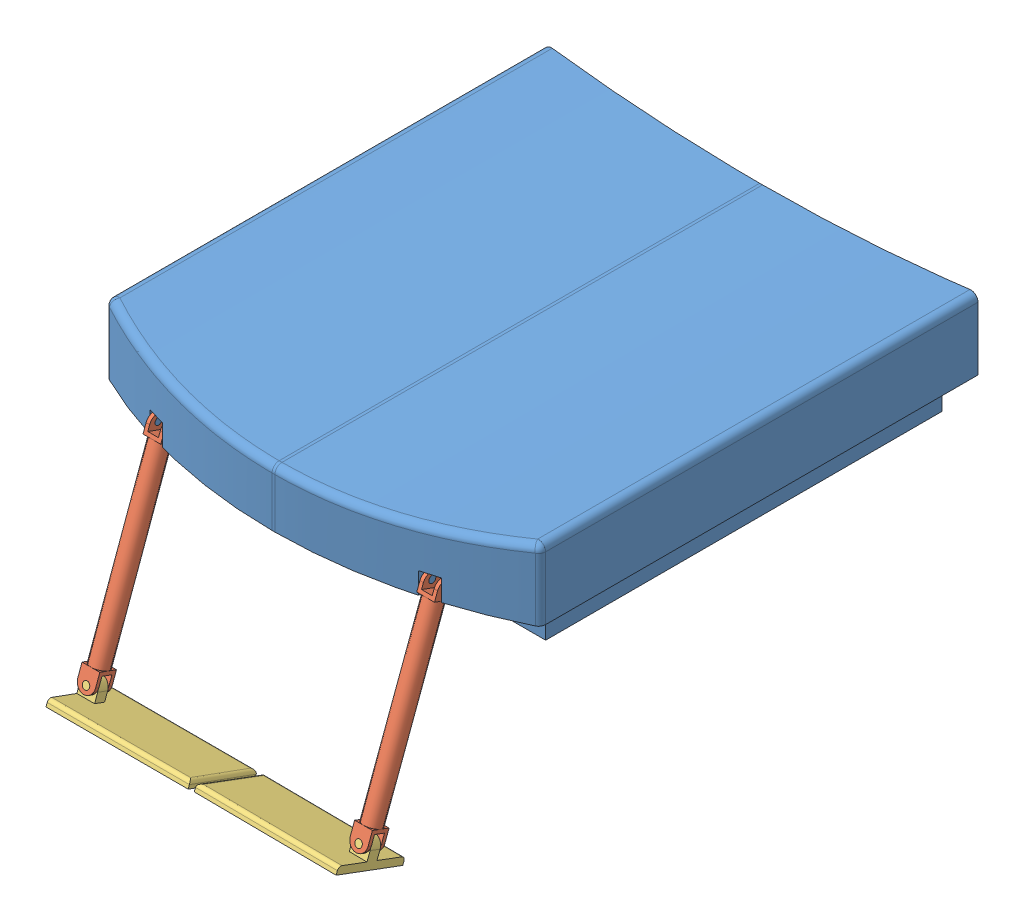
SolidWorks assembly Team Project Subassembly Connor (1), configuration Default. Lengths in mm.
Overall size (610 401.42 802.5).
5 component instances, 3 part files, 12 mates.
Components (placement in the parent):
- Bottom Rest-1: Bottom Rest [Default] at (302.6868 294.5233 402.6351) size (610 177.85 685.8)
- Connection Rods-1: Connection Rods [Default] at (110.1868 178.0175 755.1384) x (1 0 0) z (0 0.343024 0.939327) size (25 305 25)
- Foot Rest-1: Foot Rest [Default] at (197.6766 18.2985 813.4647) x (1 -0.000383 0.00014) z (0 0.343024 0.939327) size (200 35 100)
- Foot Rest-2: Foot Rest [Default] at (407.5211 19.5845 815.1514) x (-0.999978 0.006282 -0.002341) z (0 -0.349166 -0.937061) size (200 35 100)
- Connection Rods-2: Connection Rods [Default] at (495.1868 178.3347 755.9983) x (1 0 0) z (0 0.349166 0.937061) size (25 305 25)
Mates (geometry in assembly coordinates):
- Concentric2: concentric aligned: cylinder of Connection Rods-1 through (110.1868 46.103 816.6185) axis (0 -0.343024 -0.939327) radius 5; cylinder of Foot Rest-1 through (110.1868 46.103 816.6185) axis (0 -0.343024 -0.939327) radius 5
- Coincident2: coincident anti-aligned: plane of Connection Rods-1 through (97.6868 34.9946 815.3521) normal (0 -0.343024 -0.939327); plane of Foot Rest-1 through (197.6766 20.8712 820.5097) normal (0 0.343024 0.939327)
- Concentric3: concentric aligned: cylinder of Bottom Rest-1 through (102.6868 309.5233 707.1151) axis (-1 0 0) radius 5; cylinder of Connection Rods-1 through (122.6868 309.5233 707.1151) axis (-1 0 0) radius 5
- Coincident6: coincident anti-aligned: plane of Bottom Rest-1 through (97.6868 324.5233 722.1151) normal (1 0 0); plane of Connection Rods-1 through (97.6868 295.8422 698.8037) normal (-1 0 0)
- Concentric8: concentric anti-aligned: cylinder of Bottom Rest-1 through (502.6868 309.5233 707.1151) axis (1 0 0) radius 5; cylinder of Connection Rods-2 through (507.6868 309.5233 707.1151) axis (-1 0 0) radius 5
- Coincident9: coincident anti-aligned: plane of Bottom Rest-1 through (507.6868 324.5233 722.1151) normal (-1 0 0); plane of Connection Rods-2 through (507.6868 295.7881 698.8935) normal (1 0 0)
- Concentric9: concentric anti-aligned: cylinder of Foot Rest-2 through (495.1868 38.0963 794.914) axis (0 0.349166 0.937061) radius 5; cylinder of Connection Rods-2 through (495.1868 46.8254 818.3405) axis (0 -0.349166 -0.937061) radius 5
- Coincident10: coincident anti-aligned: plane of Foot Rest-2 through (407.5211 22.2033 822.1794) normal (0 0.349166 0.937061); plane of Connection Rods-2 through (482.6868 35.709 817.1469) normal (0 -0.349166 -0.937061)
- Concentric10: concentric aligned: cylinder of Bottom Rest-1 through (117.6868 309.5233 707.1151) axis (1 0 0) radius 5; circle of Connection Rods-1
- Concentric11: concentric aligned: cylinder of Bottom Rest-1 through (487.6868 309.5233 707.1151) axis (-1 0 0) radius 5; circle of Connection Rods-2
- Concentric12: concentric anti-aligned: cylinder of Connection Rods-1 through (110.1868 46.103 816.6185) axis (0 -0.343024 -0.939327) radius 5; circle of Foot Rest-1
- Concentric13: concentric anti-aligned: cylinder of Foot Rest-2 through (495.1868 38.0963 794.914) axis (0 0.349166 0.937061) radius 5; circle of Connection Rods-2
